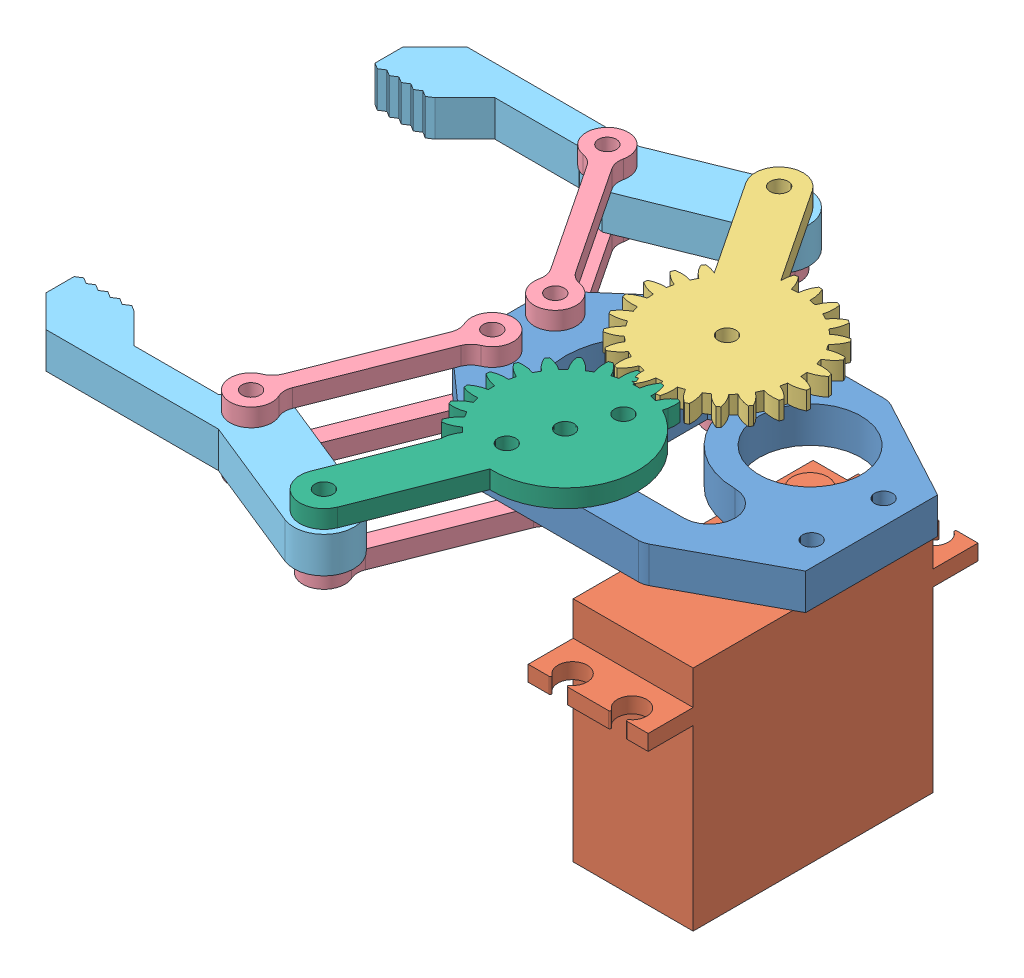
SolidWorks assembly Montagem, configuration Valor predeterminado. Lengths in mm.
Overall size (111.99 53.4 114.69).
12 component instances, 6 part files, 30 mates.
Components (placement in the parent):
- Corpo_Garra_1-2: Corpo_Garra_1 [Default] at (0 -6 0) x (0 0 -1) z (1 0 0) size (41 6 62)
- Motor H-KING-1: Motor H-KING [Valor predeterminado] at (-17.7803 -12.4 -7.5197) x (0 0 1) z (-1 0 0) size (55 44.4 20)
- Engrenagem_Garra_1-1: Engrenagem_Garra_1 [Default] at (-43.1935 0 -21.9208) x (-0.552937 0 -0.833223) z (0.833223 0 -0.552937) size (49.54 3 29.07)
- Link_Garra_1-1: Link_Garra_1 [Default] at (-69.3931 0 34.0804) x (0.367525 0 -0.930013) z (0.930013 0 0.367525) size (38 3 7)
- Link_Garra_1-2: Link_Garra_1 [Default] at (-75.1409 0 -31.0799) x (0.552937 0 0.833223) z (-0.833223 0 0.552937) size (38 3 7)
- Link_Garra_2-1: Link_Garra_2 [Default] at (-42.4885 -6 39.5703) x (0 1 0) z (0.927025 0 0.375) size (6 20.79 60.37)
- Link_Garra_1-3: Link_Garra_1 [Default] at (-48.9986 -9 42.3304) x (0.367525 0 -0.930013) z (0.930013 0 0.367525) size (38 3 7)
- Link_Garra_2-2: Link_Garra_2 [Default] at (-48.2362 0 -36.5698) x (0 -1 0) z (0.927025 0 -0.375) size (6 20.79 60.37)
- Engrenagem_Garra_2-1: Engrenagem_Garra_2 [Default] at (-30.5769 0 6.2378) x (0.69545 0 -0.718575) z (0.718575 0 0.69545) size (46.27 3 30.4)
- Link_Garra_1-4: Link_Garra_1 [Default] at (-54.7464 -9 -39.3299) x (0.552937 0 0.833223) z (-0.833223 0 0.552937) size (38 3 7)
- Link_Garra_1-5: Link_Garra_1 [Default] at (-69.3931 -9 34.0804) x (0.367525 0 -0.930013) z (0.930013 0 0.367525) size (38 3 7)
- Link_Garra_1-6: Link_Garra_1 [Default] at (-75.1409 -9 -31.0799) x (0.552937 0 0.833223) z (-0.833223 0 0.552937) size (38 3 7)
Mates (geometry in assembly coordinates):
- Coincidente2: coincident aligned: plane of Corpo_Garra_1-2 through (0 0 11) normal (1 0 0)
- Coincidente3: coincident aligned: plane of Corpo_Garra_1-2 through (0 0 0) normal (0 1 0)
- Coincidente4: coincident anti-aligned: plane of Corpo_Garra_1-2 through (0 -6 0) normal (0 0 -1)
- Concêntrico1: concentric aligned: cylinder of Corpo_Garra_1-2 through (-37.6053 0 13.5) axis (0 -1 0) radius 1.5; cylinder of Engrenagem_Garra_2-1 through (-37.6053 3 13.5) axis (0 -1 0) radius 1.5
- Coincidente5: coincident anti-aligned: plane of Corpo_Garra_1-2 through (0 0 0) normal (0 1 0); plane of Engrenagem_Garra_2-1 through (-16.2202 0 -8.5962) normal (0 -1 0)
- Concêntrico2: concentric aligned: cylinder of Corpo_Garra_1-2 through (-37.6053 0 13.5) axis (0 -1 0) radius 1.5; cylinder of Link_Garra_1-3 through (-37.6053 -6 13.5) axis (0 -1 0) radius 1.5
- Coincidente6: coincident anti-aligned: plane of Corpo_Garra_1-2 through (0 -6 0) normal (0 -1 0); plane of Link_Garra_1-3 through (-48.9986 -6 42.3304) normal (0 1 0)
- Concêntrico3: concentric aligned: cylinder of Corpo_Garra_1-2 through (-57.9999 0 5.25) axis (0 -1 0) radius 1.5; cylinder of Link_Garra_1-1 through (-57.9999 3 5.25) axis (0 -1 0) radius 1.5
- Coincidente7: coincident anti-aligned: plane of Corpo_Garra_1-2 through (0 0 0) normal (0 1 0); plane of Link_Garra_1-1 through (-69.3931 0 34.0804) normal (0 -1 0)
- Concêntrico4: concentric anti-aligned: cylinder of Link_Garra_2-1 through (-48.9986 0 42.3304) axis (0 -1 0) radius 1.5; cylinder of Engrenagem_Garra_2-1 through (-48.9986 0 42.3304) axis (0 1 0) radius 1.5
- Concêntrico5: concentric anti-aligned: cylinder of Link_Garra_1-3 through (-48.9986 -6 42.3304) axis (0 -1 0) radius 1.5; cylinder of Engrenagem_Garra_2-1 through (-48.9986 0 42.3304) axis (0 1 0) radius 1.5
- Coincidente8: coincident anti-aligned: plane of Link_Garra_2-1 through (-42.4885 0 39.5703) normal (0 1 0); plane of Engrenagem_Garra_2-1 through (-16.2202 0 -8.5962) normal (0 -1 0)
- Concêntrico6: concentric aligned: cylinder of Link_Garra_1-1 through (-69.3931 3 34.0804) axis (0 -1 0) radius 1.5; cylinder of Link_Garra_2-1 through (-69.3931 0 34.0804) axis (0 -1 0) radius 1.5
- Coincidente9: coincident anti-aligned: plane of Corpo_Garra_1-2 through (0 0 0) normal (0 1 0); plane of Engrenagem_Garra_1-1 through (-54.7464 0 -39.3299) normal (0 -1 0)
- Concêntrico7: concentric aligned: cylinder of Corpo_Garra_1-2 through (-37.6053 0 -13.5) axis (0 -1 0) radius 1.5; cylinder of Engrenagem_Garra_1-1 through (-37.6053 3 -13.5) axis (0 -1 0) radius 1.5
- Coincidente10: coincident aligned: plane of Corpo_Garra_1-2 through (0 0 0) normal (0 1 0); plane of Link_Garra_2-2 through (-48.2362 0 -36.5698) normal (0 1 0)
- Coincidente11: coincident anti-aligned: plane of Corpo_Garra_1-2 through (0 0 0) normal (0 1 0); plane of Link_Garra_1-2 through (-75.1409 0 -31.0799) normal (0 -1 0)
- Concêntrico8: concentric aligned: cylinder of Corpo_Garra_1-2 through (-57.9999 0 -5.25) axis (0 -1 0) radius 1.5; cylinder of Link_Garra_1-2 through (-57.9999 3 -5.25) axis (0 -1 0) radius 1.5
- Concêntrico9: concentric anti-aligned: cylinder of Link_Garra_1-2 through (-75.1409 3 -31.0799) axis (0 -1 0) radius 1.5; cylinder of Link_Garra_2-2 through (-75.1409 -6 -31.0799) axis (0 1 0) radius 1.5
- Coincidente12: coincident anti-aligned: plane of Corpo_Garra_1-2 through (0 -6 0) normal (0 -1 0); plane of Link_Garra_1-4 through (-54.7464 -6 -39.3299) normal (0 1 0)
- Concêntrico10: concentric aligned: cylinder of Corpo_Garra_1-2 through (-37.6053 0 -13.5) axis (0 -1 0) radius 1.5; cylinder of Link_Garra_1-4 through (-37.6053 -6 -13.5) axis (0 -1 0) radius 1.5
- Concêntrico11: concentric anti-aligned: cylinder of Link_Garra_2-2 through (-54.7464 -6 -39.3299) axis (0 1 0) radius 1.5; cylinder of Link_Garra_1-4 through (-54.7464 -6 -39.3299) axis (0 -1 0) radius 1.5
- Concêntrico12: concentric anti-aligned: cylinder of Engrenagem_Garra_1-1 through (-54.7464 3 -39.3299) axis (0 -1 0) radius 1.5; cylinder of Link_Garra_2-2 through (-54.7464 -6 -39.3299) axis (0 1 0) radius 1.5
- Concêntrico13: concentric aligned: cylinder of Corpo_Garra_1-2 through (-17.7803 0 -7.5197) axis (0 -1 0) radius 8.5; cylinder of Motor H-KING-1 through (-17.7803 -12.4 -7.5197) axis (0 -1 0) radius 2.95
- Coincidente13: coincident anti-aligned: plane of Corpo_Garra_1-2 through (0 -6 0) normal (0 -1 0); plane of Link_Garra_1-6 through (-75.1409 -6 -31.0799) normal (0 1 0)
- Coincidente14: coincident anti-aligned: plane of Corpo_Garra_1-2 through (0 -6 0) normal (0 -1 0); plane of Link_Garra_1-5 through (-69.3931 -6 34.0804) normal (0 1 0)
- Concêntrico15: concentric anti-aligned: cylinder of Link_Garra_2-2 through (-75.1409 -6 -31.0799) axis (0 1 0) radius 1.5; cylinder of Link_Garra_1-6 through (-75.1409 -6 -31.0799) axis (0 -1 0) radius 1.5
- Concêntrico16: concentric aligned: cylinder of Link_Garra_2-1 through (-69.3931 0 34.0804) axis (0 -1 0) radius 1.5; cylinder of Link_Garra_1-5 through (-69.3931 -6 34.0804) axis (0 -1 0) radius 1.5
- Concêntrico17: concentric aligned: cylinder of Corpo_Garra_1-2 through (-57.9999 0 5.25) axis (0 -1 0) radius 1.5; cylinder of Link_Garra_1-5 through (-57.9999 -6 5.25) axis (0 -1 0) radius 1.5
- Concêntrico18: concentric aligned: cylinder of Corpo_Garra_1-2 through (-57.9999 0 -5.25) axis (0 -1 0) radius 1.5; cylinder of Link_Garra_1-6 through (-57.9999 -6 -5.25) axis (0 -1 0) radius 1.5
